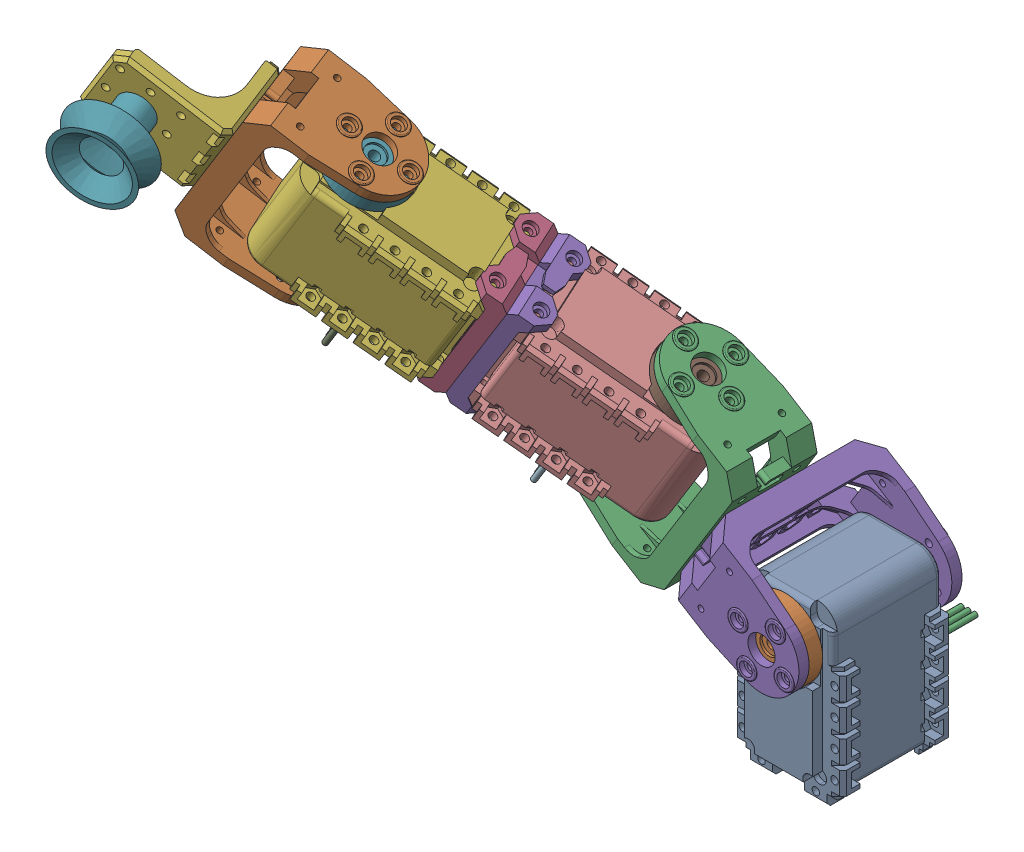
SolidWorks assembly Essai_bras_AX12_V1, configuration Défaut. Lengths in mm.
Overall size (179.34 145.81 121.16).
22 component instances, 7 part files, 23 mates.
Components (placement in the parent):
- servomoteur_ax-12-1: servomoteur_ax-12 [Default] at origin size (32 52.31 53.4)
  - AX-12_modif-1: AX-12_modif [Défaut] at (-2.6768 21.8769 -4.3025) size (32 50.06 38.01)
  - attache_ax-12-1: attache_ax-12 [Default] at (-2.6768 21.8769 12.6975) x (-0.301968 0.953318 0) z (0 0 1) size (22 22 4.7)
  - connecteur_AX-12-1: connecteur_AX-12 [Default] at (6.5732 8.6769 -17.5025) x (-1 0 0) z (0 -1 0) size (8 18.5 4)
  - connecteur_AX-12-2: connecteur_AX-12 [Default] at (-4.0768 8.6769 -17.5025) x (-1 0 0) z (0 -1 0) size (8 18.5 4)
- F2-1: F2 [Défaut] at (-2.6768 21.8769 -4.3025) x (0 0 1) z (-0.850506 0.525966 0) size (48.81 25 37)
- servomoteur_ax-12-2: servomoteur_ax-12 [Default] at (-92.7854 82.6602 25.1633) x (-0.320869 0.19843 -0.926104) z (0.525966 0.850506 0) size (32 52.31 53.4)
  - AX-12_modif-1: AX-12_modif [Défaut] at (-2.6768 21.8769 -4.3025) size (32 50.06 38.01)
  - attache_ax-12-1: attache_ax-12 [Default] at (-2.6768 21.8769 12.6975) x (-0.301968 0.953318 0) z (0 0 1) size (22 22 4.7)
  - connecteur_AX-12-1: connecteur_AX-12 [Default] at (6.5732 8.6769 -17.5025) x (-1 0 0) z (0 -1 0) size (8 18.5 4)
  - connecteur_AX-12-2: connecteur_AX-12 [Default] at (-4.0768 8.6769 -17.5025) x (-1 0 0) z (0 -1 0) size (8 18.5 4)
- servomoteur_ax-12-3: servomoteur_ax-12 [Default] at (-61.0127 63.0115 14.4299) x (0.320869 -0.19843 0.926104) z (0.525966 0.850506 0) size (32 52.31 53.4)
  - AX-12_modif-1: AX-12_modif [Défaut] at (-2.6768 21.8769 -4.3025) size (32 50.06 38.01)
  - attache_ax-12-1: attache_ax-12 [Default] at (-2.6768 21.8769 12.6975) x (-0.301968 0.953318 0) z (0 0 1) size (22 22 4.7)
  - connecteur_AX-12-1: connecteur_AX-12 [Default] at (6.5732 8.6769 -17.5025) x (-1 0 0) z (0 -1 0) size (8 18.5 4)
  - connecteur_AX-12-2: connecteur_AX-12 [Default] at (-4.0768 8.6769 -17.5025) x (-1 0 0) z (0 -1 0) size (8 18.5 4)
- F2-2: F2 [Défaut] at (-111.421 89.1259 35.8957) x (0.525966 0.850506 0) z (-0.807128 0.49914 0.315283) size (48.81 25 37)
- F2-3: F2 [Défaut] at (-46.9031 49.2271 3.6975) x (-0.525966 -0.850506 0) z (0.850506 -0.525966 0) size (48.81 25 37)
- F3-1: F3 [Défaut] at (-79.2904 69.2559 19.4261) x (-0.320869 0.19843 -0.926104) z (0.525966 0.850506 0) size (25 9 38)
- F3-2: F3 [Défaut] at (-79.2904 69.2559 19.4261) x (0.320869 -0.19843 0.926104) z (0.525966 0.850506 0) size (25 9 38)
- F9ORG-1: F9ORG [Défaut] at (-129.0544 100.0307 55.9555) x (0.26815 -0.165828 0.948998) z (0.807128 -0.49914 -0.315283) size (24 24 30)
- ventouse_coval_VSA22_M5-1: ventouse_coval_VSA22_M5 [Default] at (-139.295 106.3636 79.9768) x (0.962564 0.005662 -0.270994) z (0.039565 0.986138 0.161138) size (24 19 24)
Mates (geometry in assembly coordinates):
- Coaxiale1: concentric anti-aligned: cylinder of servomoteur_ax-12-1/attache_ax-12-1; cylinder of F2-1
- Coïncidente1: coincident anti-aligned: plane of servomoteur_ax-12-1/attache_ax-12-1 through (-2.6768 21.8769 16.6975) normal (0 0 1); plane of F2-1 through (-2.6768 21.8769 16.6975) normal (0 0 -1)
- Coïncidente2: coincident anti-aligned: plane of F2-3 through (-12.1668 55.9641 -8.8025) normal (0.850506 -0.525966 0); plane of F2-1 through (-18.2154 46.1833 -28.3025) normal (-0.850506 0.525966 0)
- Coaxiale2: concentric anti-aligned: cylinder of F2-1; cylinder of F2-3
- Coaxiale3: concentric anti-aligned: cylinder of F2-1; cylinder of F2-3
- Coïncidente3: coincident anti-aligned: plane of servomoteur_ax-12-2/AX-12_modif-1 through (-94.5566 59.8844 6.9425) normal (-0.525966 -0.850506 0); plane of F3-1 through (-86.0579 54.6287 32.1342) normal (0.525966 0.850506 0)
- Coïncidente4: coincident anti-aligned: plane of servomoteur_ax-12-2/AX-12_modif-1 through (-71.7767 83.4934 33.0616) normal (0.928871 0.256968 -0.266769); plane of F3-1 through (-71.1977 80.9472 32.6247) normal (-0.928871 -0.256968 0.266769)
- Coïncidente5: coincident anti-aligned: plane of servomoteur_ax-12-2/AX-12_modif-1 through (-79.3805 88.2199 11.1031) normal (-0.320869 0.19843 -0.926104); plane of F3-1 through (-82.9804 71.5378 8.7759) normal (0.320869 -0.19843 0.926104)
- Coïncidente6: coincident anti-aligned: plane of servomoteur_ax-12-2/attache_ax-12-1 through (-100.3757 106.9865 35.8957) normal (0.525966 0.850506 0); plane of F2-2 through (-100.3757 106.9865 35.8957) normal (-0.525966 -0.850506 0)
- Coaxiale4: concentric anti-aligned: cylinder of servomoteur_ax-12-2/attache_ax-12-1; cylinder of F2-2
- Coïncidente7: coincident anti-aligned: plane of servomoteur_ax-12-3/attache_ax-12-1 through (-35.8578 67.0877 3.6975) normal (0.525966 0.850506 0); plane of F2-3 through (-35.8578 67.0877 3.6975) normal (-0.525966 -0.850506 0)
- Coaxiale5: concentric aligned: cylinder of servomoteur_ax-12-3/attache_ax-12-1; cylinder of F2-3
- Coïncidente8: coincident anti-aligned: plane of servomoteur_ax-12-3/AX-12_modif-1 through (-73.7235 84.6255 3.7298) normal (0.525966 0.850506 0); plane of F3-2 through (-64.5011 78.9223 29.8706) normal (-0.525966 -0.850506 0)
- Coïncidente9: coincident anti-aligned: plane of servomoteur_ax-12-3/AX-12_modif-1 through (-89.6738 56.1123 7.7899) normal (-0.320869 0.19843 -0.926104); plane of F3-2 through (-82.9804 71.5378 8.7759) normal (0.320869 -0.19843 0.926104)
- Coïncidente10: coincident anti-aligned: plane of servomoteur_ax-12-3/AX-12_modif-1 through (-62.4561 77.7294 27.3015) normal (-0.185044 0.945829 0.266769); plane of F3-2 through (-64.4239 76.7582 29.3802) normal (0.185044 -0.945829 -0.266769)
- Coïncidente11: coincident anti-aligned: plane of F9ORG-1 through (-129.4466 114.3825 32.2306) normal (0.807128 -0.49914 -0.315283); plane of F2-2 through (-148.3814 83.7643 32.2306) normal (-0.807128 0.49914 0.315283)
- Coaxiale6: concentric anti-aligned: cylinder of F2-2; cylinder of F9ORG-1
- Coaxiale7: concentric anti-aligned: cylinder of F2-2; cylinder of F9ORG-1
- Coïncidente12: coincident anti-aligned: plane of F3-1 through (-79.2904 69.2559 19.4261) normal (0.787657 -0.487099 -0.377268); plane of F3-2 through (-79.2904 69.2559 19.4261) normal (-0.787657 0.487099 0.377268)
- Coaxiale8: concentric anti-aligned: cylinder of F3-1; cylinder of F3-2
- Coïncidente13: coincident aligned: plane of F3-1 through (-73.3079 87.8959 7.8498) normal (-0.320869 0.19843 -0.926104); plane of F3-2 through (-93.2946 55.5766 7.8498) normal (-0.320869 0.19843 -0.926104)
- Coaxiale9: concentric aligned: cylinder of F9ORG-1; cylinder of ventouse_coval_VSA22_M5-1
- Coïncidente14: coincident anti-aligned: plane of F9ORG-1 through (-122.7429 110.2368 55.9555) normal (0.26815 -0.165828 0.948998); plane of ventouse_coval_VSA22_M5-1 through (-139.5771 109.5427 60.5909) normal (-0.26815 0.165828 -0.948998)
